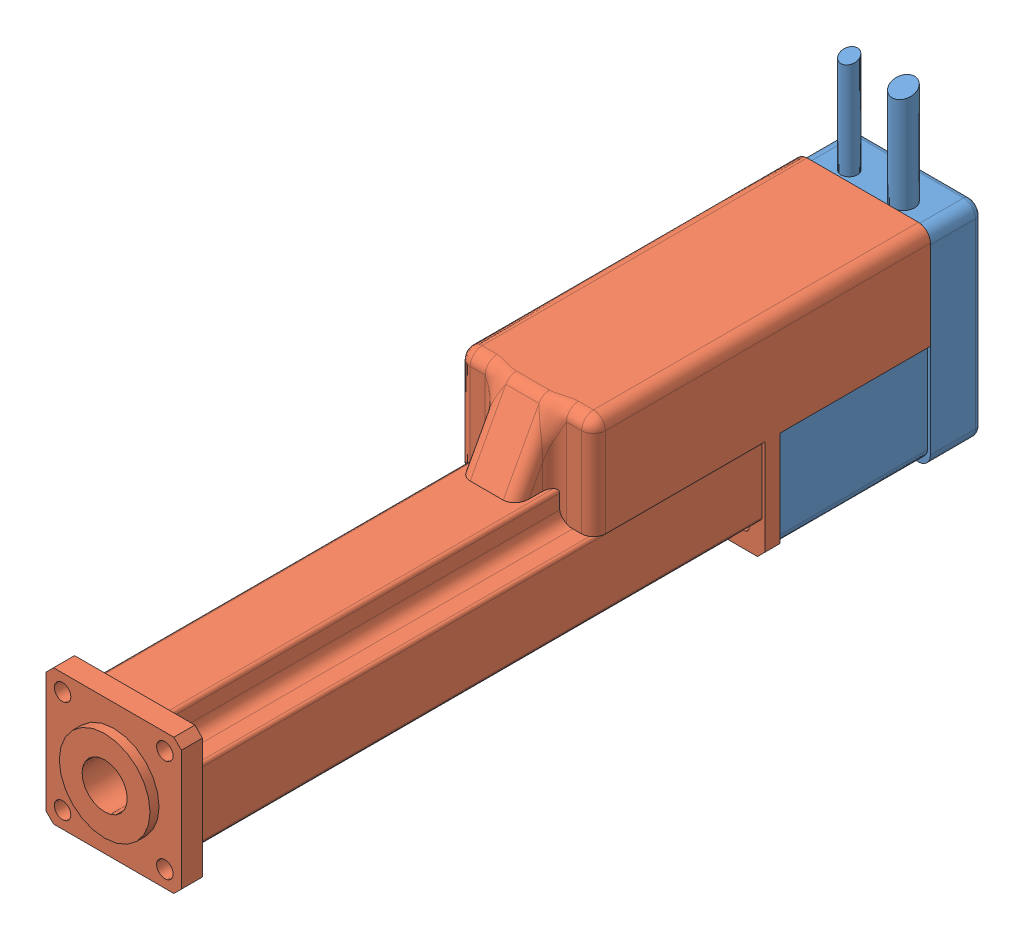
SolidWorks assembly corps_verin, configuration Défaut. Lengths in mm.
Overall size (45 102.68 269).
2 component instances, 2 part files, 3 mates.
Components (placement in the parent):
- RSA04-1: RSA04 [Défaut] at (-95.9835 24.6976 97.5002) size (44 102.68 87.5)
- prt-SCN5-150-2: prt-SCN5-150 [Défaut] at (-96.4835 25.1976 97.5002) size (45 68.14 252)
Mates (geometry in assembly coordinates):
- Coïncidente8: coincident: plane of RSA04-1 through (-95.9835 24.6976 97.5002) normal (0 0 1); plane of ? through (-149.0981 25.1976 97.5002) normal (0 0 -1)
- Coïncidente9: coincident: plane of RSA04-1 through (-113.9835 3.6976 97.5002) normal (0 -1 0); plane of ? through (-149.0981 3.6976 102.5002) normal (0 -1 0)
- Coïncidente10: coincident aligned: plane of RSA04-1 through (-74.9835 6.6976 97.5002) normal (1 0 0); plane of ? through (-127.5981 25.1976 102.5002) normal (1 0 0)
